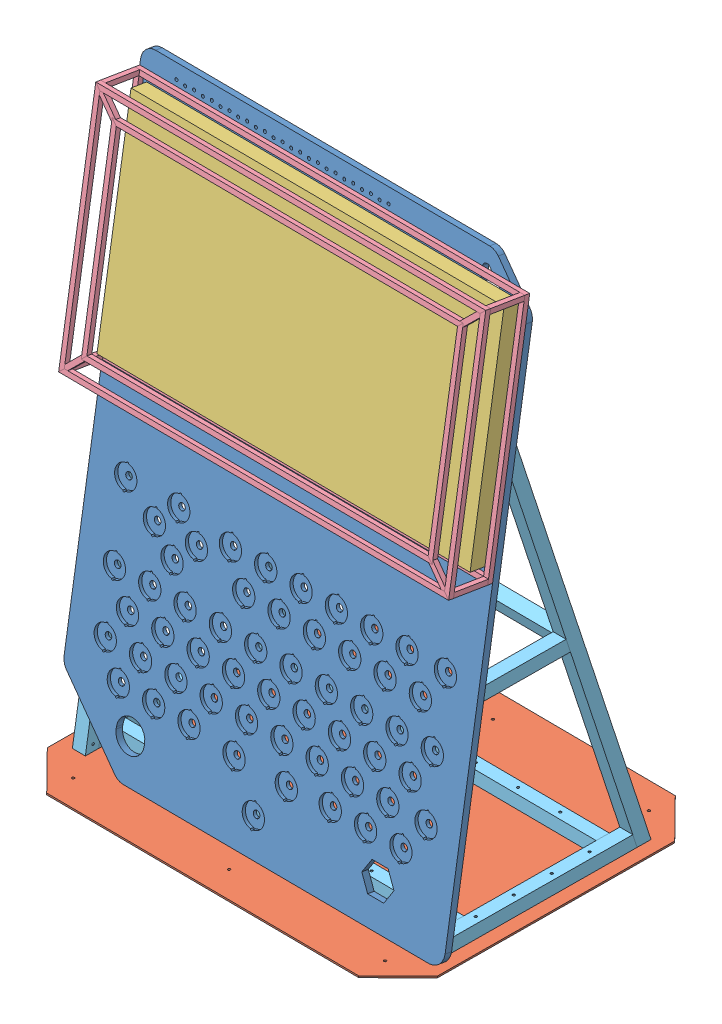
SolidWorks assembly MEGA POCKET CHIP ASSYr2, configuration Default. Lengths in mm.
Overall size (1532.85 2192.95 1230.28).
5 component instances, 5 part files, 12 mates.
Components (placement in the parent):
- PCB-1: PCB [ALL] at (413.4513 1489.7436 1810.9938) x (0.999973 0 0.007289) z (-0.007199 0.156434 0.987662) size (1524 2209.83 25.4)
- Base-1: Base [To be delivered<As Machined>] at (414.4918 -28.0453 1640.6515) x (-0.007289 0 0.999973) z (0.999973 0 0.007289) size (1219.2 6.35 1524)
- TV-1: TV [Default] at (-1320.3103 1635.9072 1862.6443) x (-0.999973 0 -0.007289) z (0.007199 -0.156434 -0.987662) size (1457.96 838.2 60.96)
- BEZEL-1: BEZEL [Default<As Machined>] at (866.9902 1405.0504 2017.3793) x (0.999973 0 0.007289) z (-0.007199 0.156434 0.987662) size (1524 914.4 171.45)
- baser2-1: baser2 [Default<As Machined>] at (1096.8592 36.9911 2114.0625) x (0.999973 0 0.007289) z (-0.007289 0 0.999973) size (1422.4 1986.18 826.79)
Mates (geometry in assembly coordinates):
- Width14: width anti-aligned: plane of baser2-1 through (1128.45 22.7547 1264.8455) normal (0.999973 0 0.007289); plane of baser2-1 through (-293.9122 -28.0453 1254.4777) normal (-0.999973 0 -0.007289); plane of Base-1 through (-343.0446 -34.3953 1025.5134) normal (-0.999973 0 -0.007289); plane of Base-1 through (1180.9149 -34.3953 1036.6219) normal (0.999973 0 0.007289)
- Parallel17: parallel anti-aligned: plane of PCB-1 through (-75.1248 22.1292 2039.886) normal (0.007199 -0.156434 -0.987662); plane of baser2-1 through (1071.9143 1.3281 2051.5416) normal (-0.007199 0.156434 0.987662)
- Coincident69: coincident anti-aligned: plane of PCB-1 through (-75.3077 26.1027 2064.9726) normal (-0.007199 0.156434 0.987662); plane of TV-1 through (-1319.8714 1626.3709 1802.4364) normal (0.007199 -0.156434 -0.987662)
- Width15: width anti-aligned: plane of TV-1 through (1142.6717 2051.3346 1753.0769) normal (0.999973 0 0.007289); plane of TV-1 through (-315.2496 2051.3346 1742.4499) normal (-0.999973 0 -0.007289); plane of PCB-1 through (-349.5665 927.1854 1920.2522) normal (-0.999973 0 -0.007289); plane of PCB-1 through (1173.3584 30.9939 2073.2996) normal (0.999973 0 0.007289)
- Width16: width anti-aligned: plane of baser2-1 through (1123.0787 -6.6188 2001.7387) normal (0.999973 0 0.007289); plane of baser2-1 through (-299.6493 1.3281 2041.544) normal (-0.999973 0 -0.007289); plane of PCB-1 through (-349.5665 927.1854 1920.2522) normal (-0.999973 0 -0.007289); plane of PCB-1 through (1173.3584 30.9939 2073.2996) normal (0.999973 0 0.007289)
- Coincident71: coincident anti-aligned: plane of PCB-1 through (-75.1248 22.1292 2039.886) normal (0.007199 -0.156434 -0.987662); plane of baser2-1 through (-272.0488 1907.9617 1739.7561) normal (-0.007199 0.156434 0.987662)
- Width17: width anti-aligned: plane of BEZEL-1 through (1166.1878 2070.15 1750.2682) normal (-0.00114 -0.987688 0.15643); plane of BEZEL-1 through (-339.7214 1204.6387 1876.3785) normal (0.00114 0.987688 -0.15643); plane of TV-1 through (1142.6717 2051.3346 1753.0769) normal (0.00114 0.987688 -0.15643); plane of TV-1 through (1141.7159 1223.4542 1884.1968) normal (-0.00114 -0.987688 0.15643)
- Width18: width anti-aligned: plane of TV-1 through (1142.6717 2051.3346 1753.0769) normal (0.999973 0 0.007289); plane of TV-1 through (-315.2496 2051.3346 1742.4499) normal (-0.999973 0 -0.007289); plane of BEZEL-1 through (-348.3733 2082.5378 1756.5541) normal (-0.999973 0 -0.007289); plane of BEZEL-1 through (1174.5653 1198.2111 1907.7225) normal (0.999973 0 0.007289)
- Coincident74: coincident anti-aligned: plane of PCB-1 through (-75.3077 26.1027 2064.9726) normal (-0.007199 0.156434 0.987662); plane of BEZEL-1 through (1155.653 1195.231 1888.7687) normal (0.007199 -0.156434 -0.987662)
- Coincident75: coincident anti-aligned: plane of Base-1 through (414.4918 -28.0453 1640.6515) normal (0 1 0); plane of baser2-1 through (-293.9122 -28.0453 1254.4777) normal (0 -1 0)
- Coincident76: coincident: line of PCB-1 through (-75.1827 -28.0453 2047.8326) axis (0.999973 0 0.007289); plane of Base-1 through (414.4918 -28.0453 1640.6515) normal (0 1 0)
- Width19: width anti-aligned: plane of Base-1 through (-343.0446 -34.3953 1025.5134) normal (0.007289 0 -0.999973); plane of Base-1 through (-351.9313 -34.3953 2244.6811) normal (-0.007289 0 0.999973); plane of baser2-1 through (-273.5172 22.7547 1941.2066) normal (-0.007289 0 0.999973); plane of baser2-1 through (-269.0627 -28.0453 1330.0988) normal (0.007289 0 -0.999973)
